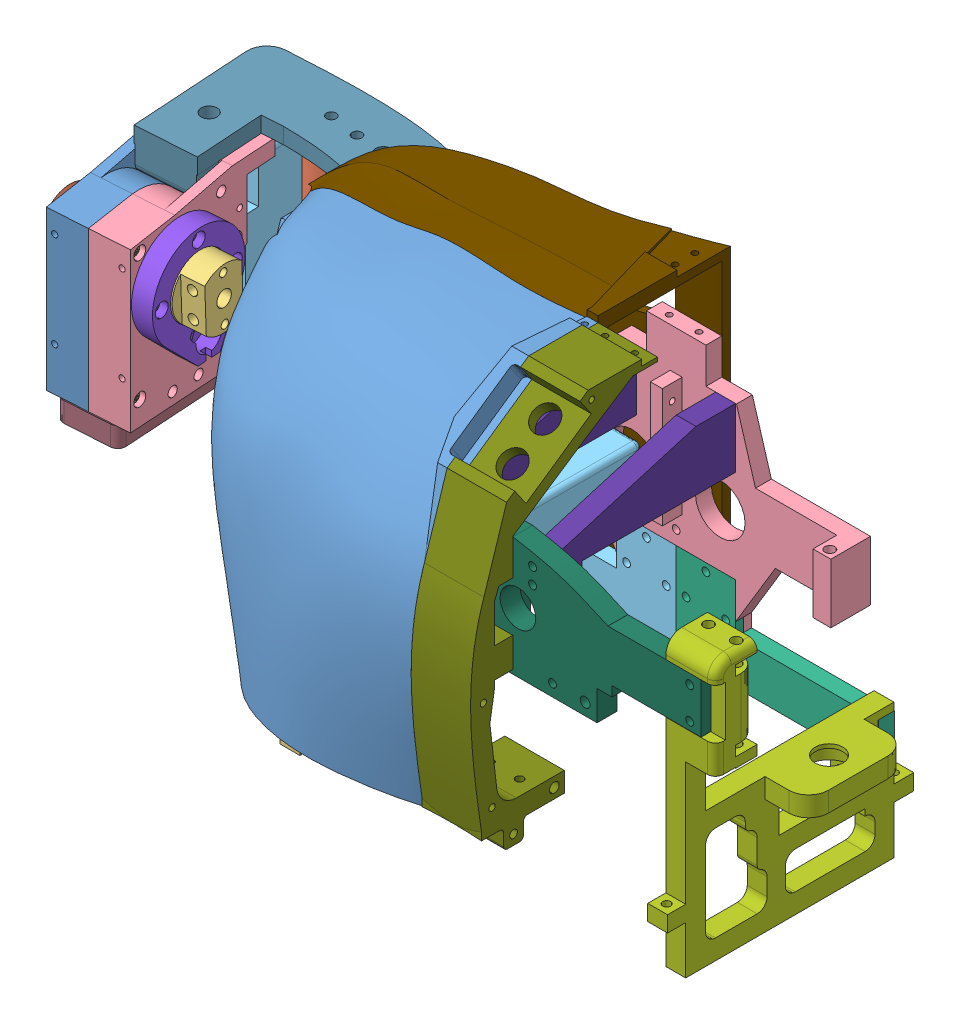
SolidWorks assembly shoulder assm, configuration Default. Lengths in mm.
Overall size (380.84 204.6 176.89).
74 component instances, 26 part files, 33 mates.
Components (placement in the parent):
- gearbox-1: gearbox [Default] at (-5.7282 -70.7252 75.9895) x (0 0 1) z (-1 0 0) size (88.25 74 125.51)
  - bottom housing-1: bottom housing [Default] at (7.4002 -24.2748 89.7718) x (1 0 0) z (0 1 0) size (87.5 78 20)
  - wormscrew-1: wormscrew [Default] at (21.4002 -4.2748 74.7718) x (-0.98645 0.164063 0) z (0 0 1) size (40 40 51)
  - driveshaft cog-1: driveshaft cog [Default] at (-6.5998 -9.2748 103.2718) x (-0.999334 0 0.036493) z (0 1 0) size (49.29 49.31 47)
  - top housing-1: top housing [Default] at (-6.5998 15.7252 103.2718) x (-1 0 0) z (0 -1 0) size (87.5 78 40)
  - HS-805BB-1: HS-805BB [Default] at (2.9002 10.7252 28.6693) x (1 0 0) z (0 -1 0) size (83 68.8 30)
  - 608ZZ-4: 608ZZ [Default] at (21.4002 -4.2748 120.5718) x (0.996867 0.079098 0) z (0 0 1) size (22 22 7)
  - 6806 30x42x7-1: 6806 30x42x7 [Default] at (-6.5998 -15.2748 103.2718) x (0.979879 0 0.199591) z (0 -1 0) size (42 42 7)
  - 6806 30x42x7-2: 6806 30x42x7 [Default] at (-6.5998 2.7252 103.2718) x (0.968275 0 0.249889) z (0 1 0) size (42 42 7)
  - pot holder-1: pot holder [Default] at (-6.5998 15.7252 103.2718) x (0 0 -1) z (0 1 0) size (50 60 10)
  - cog brace-1: cog brace [Default] at (18.6002 10.0252 104.6718) x (-1 0 0) z (0 -1 0) size (8.5 22.65 3)
  - pot cog-1: pot cog [Default] at (18.6002 10.0252 97.7718) x (0.754384 0 -0.656434) z (0 1 0) size (28 27.88 7.9)
  - driveshaft-1: driveshaft [Default] at (-6.5998 -9.2748 103.2718) x (0.999334 0 -0.036493) z (0 -1 0) size (36.44 35.48 27)
  - Pan Head Cross Recess Screw_ISO-22: Pan Head Cross Recess Screw_ISO [ISO 7045 - M3 x 10 - Z --- 10N] at (-26.5998 23.1252 103.2718) x (0 -1 0) z (0 0 1) size (12.35 5.6 5.6)
  - Pan Head Cross Recess Screw_ISO-23: Pan Head Cross Recess Screw_ISO [ISO 7045 - M3 x 10 - Z --- 10N] at (-6.5998 23.1252 123.2718) x (0 -1 0) z (0.495758 0 0.868461) size (12.35 5.6 5.6)
  - Pan Head Cross Recess Screw_ISO-24: Pan Head Cross Recess Screw_ISO [ISO 7045 - M3 x 10 - Z --- 10N] at (-6.5998 23.1252 83.2718) x (0 -1 0) z (0.927545 0 0.373711) size (12.35 5.6 5.6)
  - Pan Head Cross Recess Screw_ISO-3: Pan Head Cross Recess Screw_ISO [ISO 7045 - M5 x 12 - Z --- 12N] at (-34.5998 -13.2748 42.0718) x (0 0 1) z (-1 0 0) size (15.63 9.5 9.5)
  - Pan Head Cross Recess Screw_ISO-4: Pan Head Cross Recess Screw_ISO [ISO 7045 - M5 x 12 - Z --- 12N] at (-34.5998 4.7252 42.0718) x (0 0 1) z (-1 0 0) size (15.63 9.5 9.5)
  - Pan Head Cross Recess Screw_ISO-9: Pan Head Cross Recess Screw_ISO [ISO 7045 - M3 x 30 - Z --- 25N] at (36.9002 14.1252 123.7718) x (0 -1 0) z (0 0 1) size (32.35 5.6 5.6)
  - Pan Head Cross Recess Screw_ISO-13: Pan Head Cross Recess Screw_ISO [ISO 7045 - M3 x 30 - Z --- 25N] at (-18.0998 -22.6748 69.7718) x (0 1 0) z (0 0 1) size (32.35 5.6 5.6)
  - Pan Head Cross Recess Screw_ISO-14: Pan Head Cross Recess Screw_ISO [ISO 7045 - M3 x 30 - Z --- 25N] at (34.9002 14.1252 82.7718) x (0 -1 0) z (-0.981395 0 -0.191999) size (32.35 5.6 5.6)
  - Pan Head Cross Recess Screw_ISO-15: Pan Head Cross Recess Screw_ISO [ISO 7045 - M3 x 30 - Z --- 25N] at (-5.5998 14.1252 71.7718) x (0 -1 0) z (0.38373 0 0.923445) size (32.35 5.6 5.6)
  - Pan Head Cross Recess Screw_ISO-16: Pan Head Cross Recess Screw_ISO [ISO 7045 - M2 x 6 - Z --- 6N] at (18.6002 6.9252 115.2718) x (0 1 0) z (0.879308 0 -0.476254) size (7.57 4 4)
  - Pan Head Cross Recess Screw_ISO-18: Pan Head Cross Recess Screw_ISO [ISO 7045 - M3 x 5 - Z --- 5N] at (-5.9795 -13.6748 120.2605) x (0 1 0) z (-0.276322 0 0.961065) size (7.35 5.6 5.6)
  - Pan Head Cross Recess Screw_ISO-19: Pan Head Cross Recess Screw_ISO [ISO 7045 - M3 x 5 - Z --- 5N] at (7.8026 -13.6748 94.2402) x (0 1 0) z (0 0 1) size (7.35 5.6 5.6)
  - Pan Head Cross Recess Screw_ISO-20: Pan Head Cross Recess Screw_ISO [ISO 7045 - M3 x 5 - Z --- 5N] at (-21.6227 -13.6748 95.3147) x (0 1 0) z (-0.051559 0 0.99867) size (7.35 5.6 5.6)
  - Pan Head Cross Recess Screw_ISO-21: Pan Head Cross Recess Screw_ISO [ISO 7045 - M3 x 30 - Z --- 25N] at (-27.0895 14.1252 123.7718) x (0 -1 0) z (-0.304842 0 0.952403) size (32.35 5.6 5.6)
  - Pan Head Cross Recess Screw_ISO-2: Pan Head Cross Recess Screw_ISO [ISO 7045 - M5 x 12 - Z --- 12N] at (40.4002 4.7252 42.0718) x (0 0 1) z (0.747712 -0.664023 0) size (15.63 9.5 9.5)
  - Pan Head Cross Recess Screw_ISO-1: Pan Head Cross Recess Screw_ISO [ISO 7045 - M5 x 12 - Z --- 12N] at (40.4002 -13.2748 42.0718) x (0 0 1) z (0.337086 -0.941474 0) size (15.63 9.5 9.5)
- gearbox-2: gearbox [Default] at (-220.6558 -66.0998 -11.6257) x (0 -1 0) z (0.064189 0 0.997938) size (88.25 74 125.51)
  - bottom housing-1: bottom housing [Default] at (7.4002 -24.2748 89.7718) x (1 0 0) z (0 1 0) size (87.5 78 20)
  - wormscrew-1: wormscrew [Default] at (21.4002 -4.2748 74.7718) x (-0.98645 0.164063 0) z (0 0 1) size (40 40 51)
  - driveshaft cog-1: driveshaft cog [Default] at (-6.5998 -9.2748 103.2718) x (-0.999334 0 0.036493) z (0 1 0) size (49.29 49.31 47)
  - top housing-1: top housing [Default] at (-6.5998 15.7252 103.2718) x (-1 0 0) z (0 -1 0) size (87.5 78 40)
  - HS-805BB-1: HS-805BB [Default] at (2.9002 10.7252 28.6693) x (1 0 0) z (0 -1 0) size (83 68.8 30)
  - 608ZZ-4: 608ZZ [Default] at (21.4002 -4.2748 120.5718) x (0.996867 0.079098 0) z (0 0 1) size (22 22 7)
  - 6806 30x42x7-1: 6806 30x42x7 [Default] at (-6.5998 -15.2748 103.2718) x (0.979879 0 0.199591) z (0 -1 0) size (42 42 7)
  - 6806 30x42x7-2: 6806 30x42x7 [Default] at (-6.5998 2.7252 103.2718) x (0.968275 0 0.249889) z (0 1 0) size (42 42 7)
  - pot holder-1: pot holder [Default] at (-6.5998 15.7252 103.2718) x (0 0 -1) z (0 1 0) size (50 60 10)
  - cog brace-1: cog brace [Default] at (18.6002 10.0252 104.6718) x (-1 0 0) z (0 -1 0) size (8.5 22.65 3)
  - pot cog-1: pot cog [Default] at (18.6002 10.0252 97.7718) x (0.754384 0 -0.656434) z (0 1 0) size (28 27.88 7.9)
  - driveshaft-1: driveshaft [Default] at (-6.5998 -9.2748 103.2718) x (0.999334 0 -0.036493) z (0 -1 0) size (36.44 35.48 27)
  - Pan Head Cross Recess Screw_ISO-22: Pan Head Cross Recess Screw_ISO [ISO 7045 - M3 x 10 - Z --- 10N] at (-26.5998 23.1252 103.2718) x (0 -1 0) z (0 0 1) size (12.35 5.6 5.6)
  - Pan Head Cross Recess Screw_ISO-23: Pan Head Cross Recess Screw_ISO [ISO 7045 - M3 x 10 - Z --- 10N] at (-6.5998 23.1252 123.2718) x (0 -1 0) z (0.495758 0 0.868461) size (12.35 5.6 5.6)
  - Pan Head Cross Recess Screw_ISO-24: Pan Head Cross Recess Screw_ISO [ISO 7045 - M3 x 10 - Z --- 10N] at (-6.5998 23.1252 83.2718) x (0 -1 0) z (0.927545 0 0.373711) size (12.35 5.6 5.6)
  - Pan Head Cross Recess Screw_ISO-3: Pan Head Cross Recess Screw_ISO [ISO 7045 - M5 x 12 - Z --- 12N] at (-34.5998 -13.2748 42.0718) x (0 0 1) z (-1 0 0) size (15.63 9.5 9.5)
  - Pan Head Cross Recess Screw_ISO-4: Pan Head Cross Recess Screw_ISO [ISO 7045 - M5 x 12 - Z --- 12N] at (-34.5998 4.7252 42.0718) x (0 0 1) z (-1 0 0) size (15.63 9.5 9.5)
  - Pan Head Cross Recess Screw_ISO-9: Pan Head Cross Recess Screw_ISO [ISO 7045 - M3 x 30 - Z --- 25N] at (36.9002 14.1252 123.7718) x (0 -1 0) z (0 0 1) size (32.35 5.6 5.6)
  - Pan Head Cross Recess Screw_ISO-13: Pan Head Cross Recess Screw_ISO [ISO 7045 - M3 x 30 - Z --- 25N] at (-18.0998 -22.6748 69.7718) x (0 1 0) z (0 0 1) size (32.35 5.6 5.6)
  - Pan Head Cross Recess Screw_ISO-14: Pan Head Cross Recess Screw_ISO [ISO 7045 - M3 x 30 - Z --- 25N] at (34.9002 14.1252 82.7718) x (0 -1 0) z (-0.981395 0 -0.191999) size (32.35 5.6 5.6)
  - Pan Head Cross Recess Screw_ISO-15: Pan Head Cross Recess Screw_ISO [ISO 7045 - M3 x 30 - Z --- 25N] at (-5.5998 14.1252 71.7718) x (0 -1 0) z (0.38373 0 0.923445) size (32.35 5.6 5.6)
  - Pan Head Cross Recess Screw_ISO-16: Pan Head Cross Recess Screw_ISO [ISO 7045 - M2 x 6 - Z --- 6N] at (18.6002 6.9252 115.2718) x (0 1 0) z (0.879308 0 -0.476254) size (7.57 4 4)
  - Pan Head Cross Recess Screw_ISO-18: Pan Head Cross Recess Screw_ISO [ISO 7045 - M3 x 5 - Z --- 5N] at (-5.9795 -13.6748 120.2605) x (0 1 0) z (-0.276322 0 0.961065) size (7.35 5.6 5.6)
  - Pan Head Cross Recess Screw_ISO-19: Pan Head Cross Recess Screw_ISO [ISO 7045 - M3 x 5 - Z --- 5N] at (7.8026 -13.6748 94.2402) x (0 1 0) z (0 0 1) size (7.35 5.6 5.6)
  - Pan Head Cross Recess Screw_ISO-20: Pan Head Cross Recess Screw_ISO [ISO 7045 - M3 x 5 - Z --- 5N] at (-21.6227 -13.6748 95.3147) x (0 1 0) z (-0.051559 0 0.99867) size (7.35 5.6 5.6)
  - Pan Head Cross Recess Screw_ISO-21: Pan Head Cross Recess Screw_ISO [ISO 7045 - M3 x 30 - Z --- 25N] at (-27.0895 14.1252 123.7718) x (0 -1 0) z (-0.304842 0 0.952403) size (32.35 5.6 5.6)
  - Pan Head Cross Recess Screw_ISO-2: Pan Head Cross Recess Screw_ISO [ISO 7045 - M5 x 12 - Z --- 12N] at (40.4002 4.7252 42.0718) x (0 0 1) z (0.747712 -0.664023 0) size (15.63 9.5 9.5)
  - Pan Head Cross Recess Screw_ISO-1: Pan Head Cross Recess Screw_ISO [ISO 7045 - M5 x 12 - Z --- 12N] at (40.4002 -13.2748 42.0718) x (0 0 1) z (0.337086 -0.941474 0) size (15.63 9.5 9.5)
- bracket bottom-2: bracket bottom [Default] at (-158.7915 -125.5 85.1308) x (0.997938 0 -0.064189) z (0 1 0) size (146.28 120.67 30)
- bracket top-1: bracket top [Default] at (-233.937 -19.5 89.9643) x (-0.997938 0 0.064189) z (0 -1 0) size (146.28 120.67 55)
- front full breast strut-1: front full breast strut [Default] at (0 -67.5 134.7861) x (-1 0 0) z (0 0 -1) size (220 60 20)
- shoulder cover-1: shoulder cover [Default] at (-221.7242 -15.4272 59.4748) x (0.992805 0 -0.119741) z (0 -1 0) size (101.77 152.02 80) (hidden)
- middle section-1: middle section [Default] at (-15 -62.4387 -5.0103) x (0 0 -1) z (1 0 0) size (173 183.87 186.02)
- middle strut-1: middle strut [Default] at (-30 -43 81.1397) x (0 0 -1) z (1 0 0) size (87.5 38 10)
- shoulder cover back-1: shoulder cover back [Default] at (-15 -62.4387 31.8032) x (0 0 1) z (-1 0 0) size (79.32 175.49 155.07)
- shoulder cover front-1: shoulder cover front [Default] at (-15 -62.4387 31.8032) x (0 0 1) z (-1 0 0) size (119.43 177.15 158.4)
- shoulder mount brace-1: shoulder mount brace [Default] at (-181.6414 -115.5 23.1992) x (0.991679 0 0.128737) z (0 1 0) size (30 30 88)
- left brace-1: left brace [Default] at (-92.2288 -140.9484 87.957) x (0 0 1) z (-1 0 0) size (124.15 144.2 32)
- back plate assm-1: back plate assm [Default] at (0 -50 29.3897) size (204 142 20)
  - back plate-1: back plate [Default] at origin size (180 120 20)
  - back plate bottom mount R-1: back plate bottom mount R [Default] at (-51 -91 8) x (-1 0 0) z (0 0 -1) size (102 47 8)
  - back plate bottom mount L-1: back plate bottom mount L [Default] at (51 -91 8) x (-1 0 0) z (0 0 -1) size (102 47 8)
- middle strut-2: middle strut [Default] at (20 -43 81.1397) x (0 0 -1) z (1 0 0) size (87.5 38 10)
- right brace-1: right brace [Default] at (92.2 -140.9484 87.8535) x (0 0 -1) z (1 0 0) size (124.15 144.2 32)
Mates (geometry in assembly coordinates):
- Coincident56: coincident anti-aligned: plane of gearbox-2/bottom housing-1 through (-234.642 -112 71.2147) normal (0.997938 0 -0.064189); plane of bracket bottom-2 through (-232.4439 -102.5 105.3876) normal (-0.997938 0 0.064189)
- Coincident57: coincident: circle of gearbox-2/bottom housing-1; cylinder of bracket bottom-2
- Coincident59: coincident anti-aligned: plane of gearbox-2/bottom housing-1 through (-195.885 -27.5 60.7052) normal (0 1 0); plane of bracket top-1 through (-169.2492 -27.5 4.1997) normal (0 -1 0)
- Coincident60: coincident anti-aligned: plane of gearbox-2/bottom housing-1 through (-235.1555 -27.5 63.2312) normal (0.997938 0 -0.064189); plane of bracket top-1 through (-235.1129 -40.5 63.8932) normal (-0.997938 0 0.064189)
- Coincident62: coincident aligned: plane of bracket bottom-2 through (-237.8533 -103 29.0774) normal (-0.064189 0 -0.997938); plane of bracket top-1 through (-207.9152 -35 27.1518) normal (-0.064189 0 -0.997938)
- Parallel2: parallel aligned: plane of bracket bottom-2 through (-148.7704 -125.5 6.8704) normal (0 -1 0); plane of shoulder cover-1 through (-263.3584 -95.4272 123.1395) normal (0 -1 0)
- Lock10: lock: 
- Coincident92: coincident aligned: circle of front full breast strut-1; circle of middle strut-1
- Concentric32: concentric aligned: cylinder of gearbox-1/driveshaft cog-1; cylinder of bracket top-1
- Coincident128: coincident anti-aligned: circle of front full breast strut-1; circle of middle section-1
- Concentric38: concentric aligned: cylinder of middle section-1; cylinder of ?
- Coincident129: coincident anti-aligned: plane of middle section-1 through (-15 -115.5744 155.9111) normal (-1 0 0); plane of ? through (-15 -53.6434 145.079) normal (1 0 0)
- Coincident130: coincident aligned: plane of middle section-1 through (15 0 96.7607) normal (0 1 0); plane of ? through (-15 0 -5.0103) normal (0 1 0)
- Coincident134: coincident anti-aligned: plane of gearbox-1/driveshaft cog-1 through (-123.5583 -44.5 81.0755) normal (0 1 0); plane of bracket top-1 through (-109 -44.5 69.3897) normal (0 -1 0)
- Coincident141: coincident aligned: unknown of middle section-1
- Concentric41: concentric anti-aligned: circle of gearbox-2/bottom housing-1; circle of bracket top-1
- Concentric42: concentric anti-aligned: circle of gearbox-2/bottom housing-1; circle of bracket bottom-2
- Coincident147: coincident aligned: circle of bracket top-1; cylinder of shoulder mount brace-1
- Coincident149: coincident anti-aligned: circle of bracket top-1; circle of shoulder mount brace-1
- Coincident152: coincident anti-aligned: circle of gearbox-1/top housing-1; cylinder of left brace-1
- Concentric44: concentric anti-aligned: cylinder of gearbox-1/top housing-1; circle of left brace-1
- Coincident155: coincident anti-aligned: plane of gearbox-1/top housing-1 through (-87.5 -60 109.4276) normal (0 -1 0); plane of left brace-1 through (-102.2288 -60 124.8897) normal (0 1 0)
- Concentric45: concentric anti-aligned: cylinder of gearbox-1/top housing-1; cylinder of back plate assm-1/back plate-1
- Parallel3: parallel anti-aligned: plane of front full breast strut-1 through (-110 -85 129.7861) normal (0 0 -1); plane of left brace-1 through (-117.2288 -60 129.8897) normal (0 0 1)
- Concentric46: concentric aligned: circle of middle strut-1; circle of back plate assm-1/back plate-1
- Coincident160: coincident anti-aligned: plane of middle strut-1 through (-20 -58 37.3897) normal (0 0 -1); plane of back plate assm-1/back plate-1 through (-90 -90 37.3897) normal (0 0 1)
- Concentric47: concentric aligned: cylinder of front full breast strut-1; circle of middle strut-1
- Coincident161: coincident anti-aligned: plane of gearbox-1/top housing-1 through (-80.1544 -60 61.1475) normal (0 -1 0); plane of back plate assm-1/back plate-1 through (-90 -60 37.3897) normal (0 1 0)
- Concentric48: concentric anti-aligned: circle of back plate assm-1/back plate-1; circle of middle strut-2
- Concentric49: concentric anti-aligned: circle of back plate assm-1/back plate-1; circle of middle strut-2
- Coincident162: coincident anti-aligned: plane of back plate assm-1/back plate-1 through (-90 -90 37.3897) normal (0 0 1); plane of middle strut-2 through (30 -58 37.3897) normal (0 0 -1)
- Coincident163: coincident aligned: circle of front full breast strut-1; circle of right brace-1
- Concentric50: concentric anti-aligned: cylinder of shoulder mount brace-1; cylinder of shoulder mount brace-1
